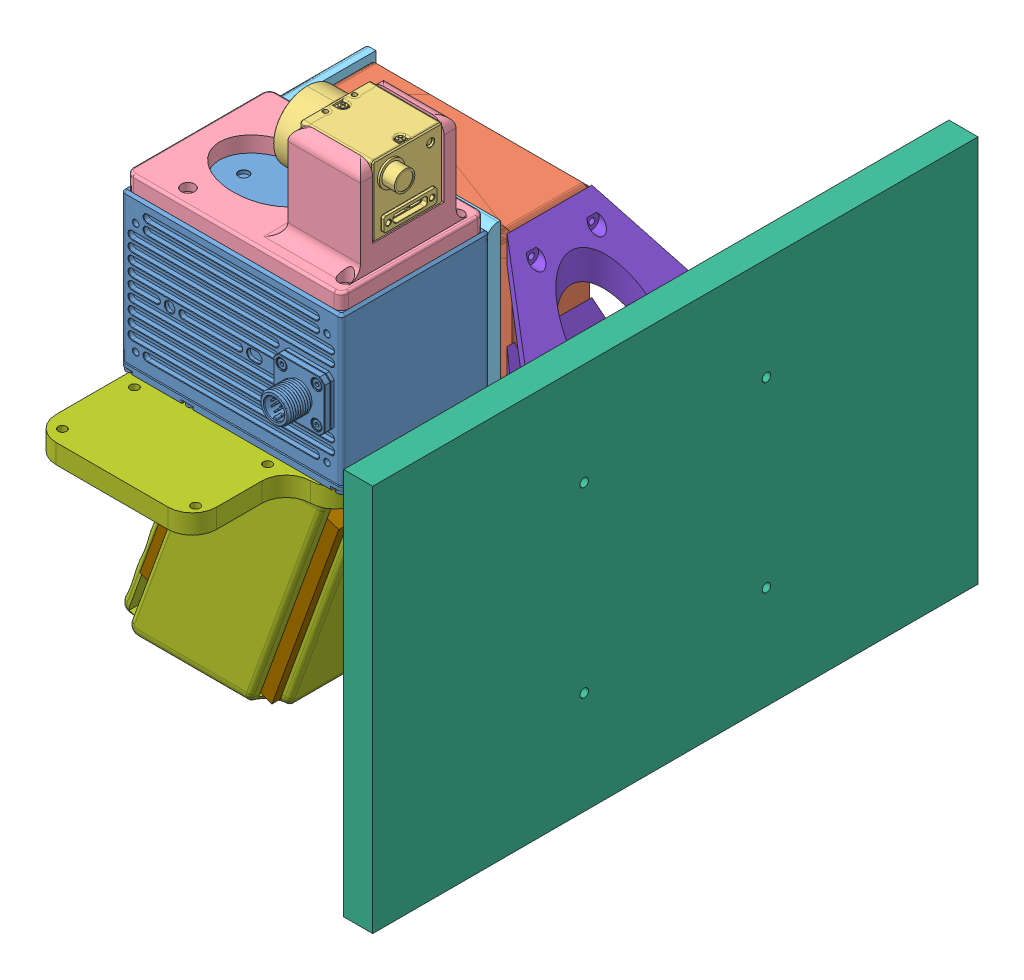
SolidWorks assembly final, configuration 默认. Lengths in mm.
Overall size (161.16 217.9 250).
12 component instances, 10 part files, 23 mates.
Components (placement in the parent):
- AVIA-1: AVIA [Default] at (-53.5064 -46.3658 122.0972) size (91.02 64.8 76.07)
  - Livox_Avia_shell_FOV.stp-1: Livox_Avia_shell_FOV.stp [Default] at origin size (1207.64 1420.81 1420.81)
    - LIVOX_AVIA.stp-1: LIVOX_AVIA.stp [Default] at origin size (91.02 64.8 76.07)
    - LIVOX_AVIA_FOV.stp-1: LIVOX_AVIA_FOV.stp [Default] at (19.97 48.3 -38.5) x (0 0 -1) z (1 0 0) size (1420.81 1420.81 1123.13) (hidden)
- DJI_manifold2-1: DJI_manifold2 [Default] at (60.2936 -28.5658 46.7972) x (1 0 0) z (0 1 0) size (91.01 35.01 61.01)
- FL2-020-R0-1: FL2-020-R0 [Default] at (37.1754 65.3342 83.8472) x (0 0 1) z (-1 0 0) size (29 29 47.76)
- T_cam_livox-1: T_cam_livox [默认] at (18.7936 40.8342 83.5972) x (0 0 -1) z (0 -1 0) size (59.2 89 45.5)
- main_livox-1: main_livox [默认] at (11.7936 1.9342 52.9972) x (1 0 0) z (0 0 -1) size (91.2 64.4 41)
- screen-1: screen [默认] at (112.2936 -58.0658 31.2972) x (0 0 -1) z (-1 0 0) size (250 160 12)
- handhold-1: handhold [默认] at (18.7936 -38.4658 83.5972) x (0 0 -1) z (0 1 0) size (140 103.94 103.37)
- fix-1: fix [默认] at (60.2936 1.9342 31.2972) x (0 0 1) z (1 0 0) size (90 136.95 41.75)
- POWER-1: POWER [默认] at (-10.3062 -120.5868 84.0972) x (0 0 -1) z (0.340658 0.940187 0) size (37 60 81)
Mates (geometry in assembly coordinates):
- 重合3: coincident anti-aligned: plane of AVIA-1/Livox_Avia_shell_FOV.stp-1/LIVOX_AVIA.stp-1 through (11.7936 34.3342 83.5972) normal (0 1 0); plane of T_cam_livox-1 through (18.7936 34.3342 83.5972) normal (0 -1 0)
- 重合4: coincident: line of AVIA-1/Livox_Avia_shell_FOV.stp-1/LIVOX_AVIA.stp-1 through (-32.2064 34.3342 53.9972) axis (1 0 0); plane of T_cam_livox-1 through (56.2936 34.3342 53.9972) normal (0 0 -1)
- 重合5: coincident: line of AVIA-1/Livox_Avia_shell_FOV.stp-1/LIVOX_AVIA.stp-1 through (56.2936 34.3342 54.4972) axis (0 0 1); plane of T_cam_livox-1 through (56.2936 34.3342 113.1972) normal (1 0 0)
- 重合6: coincident aligned: plane of FL2-020-R0-1 through (54.2936 51.3342 69.8472) normal (1 0 0); plane of T_cam_livox-1 through (54.2936 50.8342 68.8472) normal (1 0 0)
- 重合7: coincident anti-aligned: plane of FL2-020-R0-1 through (27.7936 50.8342 70.3472) normal (0 -1 0); plane of T_cam_livox-1 through (18.7936 50.8342 83.5972) normal (0 1 0)
- 重合8: coincident anti-aligned: plane of FL2-020-R0-1 through (27.7936 51.8342 98.3472) normal (0 0 1); plane of T_cam_livox-1 through (54.2936 79.8342 98.3472) normal (0 0 -1)
- 重合9: coincident anti-aligned: plane of AVIA-1/Livox_Avia_shell_FOV.stp-1/LIVOX_AVIA.stp-1 through (11.7936 3.2842 52.9972) normal (0 0 -1); plane of main_livox-1 through (11.7936 1.9342 52.9972) normal (0 0 1)
- 同心1: concentric anti-aligned: cylinder of AVIA-1/Livox_Avia_shell_FOV.stp-1/LIVOX_AVIA.stp-1 through (-27.7064 -21.0658 53.0092) axis (0 0 1) radius 1.25; cylinder of main_livox-1 through (-27.7064 -21.0658 50.1972) axis (0 0 -1) radius 2.75
- 同心2: concentric anti-aligned: cylinder of AVIA-1/Livox_Avia_shell_FOV.stp-1/LIVOX_AVIA.stp-1 through (51.2936 24.9342 53.0092) axis (0 0 1) radius 1.25; circle of main_livox-1
- 同心4: concentric anti-aligned: cylinder of DJI_manifold2-1 through (-22.7064 24.4342 18.7972) axis (1 0 0) radius 1.25; cylinder of main_livox-1 through (-30.7064 24.4342 18.7972) axis (-1 0 0) radius 1.5
- 重合14: coincident anti-aligned: plane of DJI_manifold2-1 through (-30.7064 -28.5658 11.7972) normal (-1 0 0); plane of main_livox-1 through (-30.7064 1.9342 52.9972) normal (1 0 0)
- 重合23: coincident anti-aligned: plane of AVIA-1/Livox_Avia_shell_FOV.stp-1/LIVOX_AVIA.stp-1 through (11.7936 -30.4658 83.5972) normal (0 -1 0); plane of handhold-1 through (18.7936 -30.4658 83.5972) normal (0 1 0)
- 同心14: concentric aligned: cylinder of AVIA-1/Livox_Avia_shell_FOV.stp-1/LIVOX_AVIA.stp-1 through (-13.7064 -25.8778 106.5972) axis (0 -1 0) radius 1.25; cylinder of handhold-1 through (-13.7064 -30.4658 106.5972) axis (0 -1 0) radius 1.5
- 同心15: concentric aligned: cylinder of AVIA-1/Livox_Avia_shell_FOV.stp-1/LIVOX_AVIA.stp-1 through (51.2936 -25.8778 60.5972) axis (0 -1 0) radius 1.25; cylinder of handhold-1 through (51.2936 -30.4658 60.5972) axis (0 -1 0) radius 1.5
- 同心16: concentric aligned: cylinder of fix-1 through (60.2935 -95.6908 -6.3278) axis (1 0 0) radius 2; cylinder of screen-1 through (100.2936 -95.6908 -6.3278) axis (1 0 0) radius 1.75
- 重合24: coincident anti-aligned: plane of screen-1 through (100.2936 -58.0658 31.2972) normal (-1 0 0); plane of fix-1 through (100.2936 1.9342 31.2972) normal (1 0 0)
- 同心17: concentric anti-aligned: circle of screen-1; cylinder of fix-1 through (60.2935 -95.6908 68.9222) axis (1 0 0) radius 4
- 同心18: concentric aligned: cylinder of DJI_manifold2-1 through (52.2936 24.4342 43.7972) axis (-1 0 0) radius 1.25; cylinder of fix-1 through (100.2937 24.4342 43.7972) axis (-1 0 0) radius 1.25
- 同心19: concentric aligned: cylinder of DJI_manifold2-1 through (52.2936 24.4342 18.7972) axis (-1 0 0) radius 1.25; cylinder of fix-1 through (100.2937 24.4342 18.7972) axis (-1 0 0) radius 1.25
- 重合25: coincident anti-aligned: plane of DJI_manifold2-1 through (60.2936 -28.5658 11.7972) normal (1 0 0); plane of fix-1 through (60.2936 1.9342 31.2972) normal (-1 0 0)
- 重合26: coincident anti-aligned: plane of handhold-1 through (46.6381 -48.5548 83.5972) normal (-0.940187 0.340658 0); plane of POWER-1 through (44.5525 -54.3107 102.5972) normal (0.940187 -0.340658 0)
- 重合27: coincident anti-aligned: plane of handhold-1 through (18.7936 -38.4658 102.5972) normal (0 0 -1); plane of POWER-1 through (-9.9783 -34.5525 102.5972) normal (0 0 1)
- 重合29: coincident: plane of handhold-1 through (18.7936 -130.4658 83.5972) normal (0 1 0); line of POWER-1 through (16.9592 -130.4658 102.5972) axis (0 0 -1)
